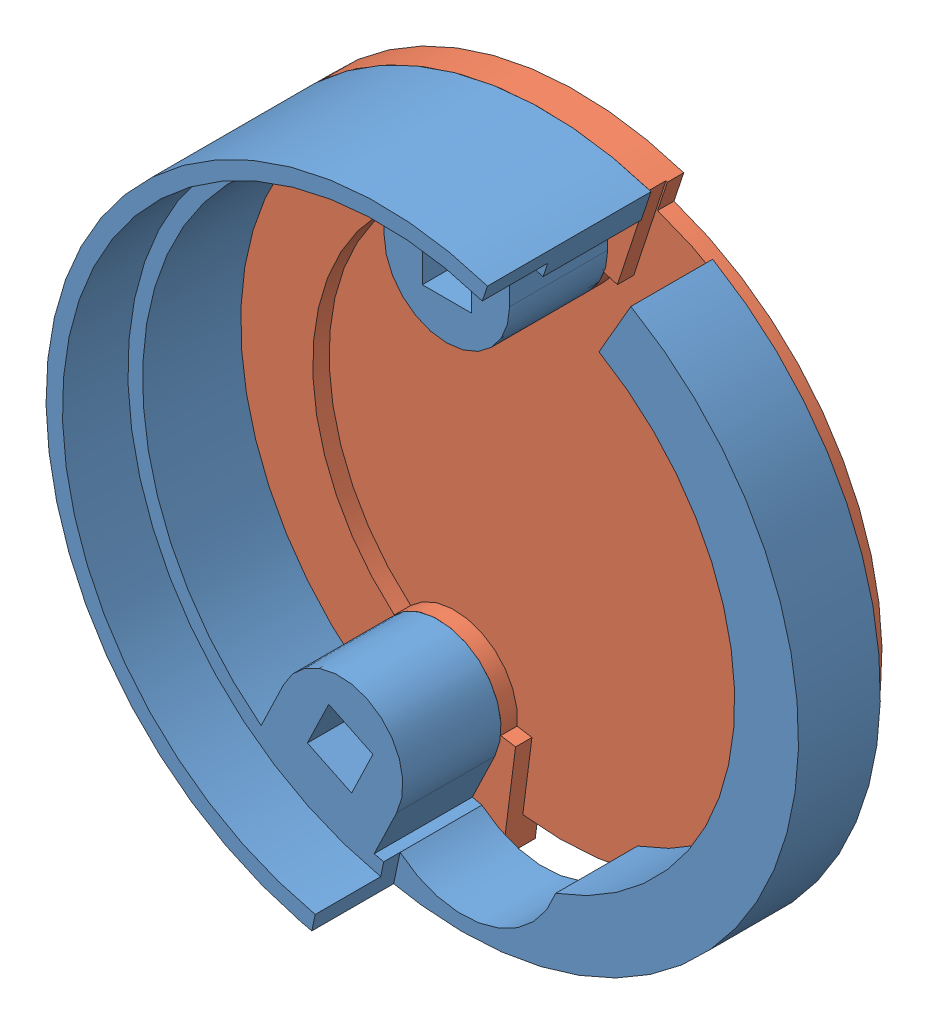
SolidWorks assembly 2_support_endstop, configuration Valor predeterminado. Lengths in mm.
Overall size (52.95 53.76 12).
2 component instances, 2 part files, 0 mates.
Components (placement in the parent):
- motor_case-endstop_support-2: motor_case-endstop_support [Valor predeterminado] at (9.4773 -39.9366 4.5727) size (41 41 10)
- motor_case-endstop_support-lid-2: motor_case-endstop_support-lid [Valor predeterminado] at (9.4773 -39.9366 2.5727) x (-0.900969 0.433884 0) z (0 0 1) size (39.1 40.83 2)
